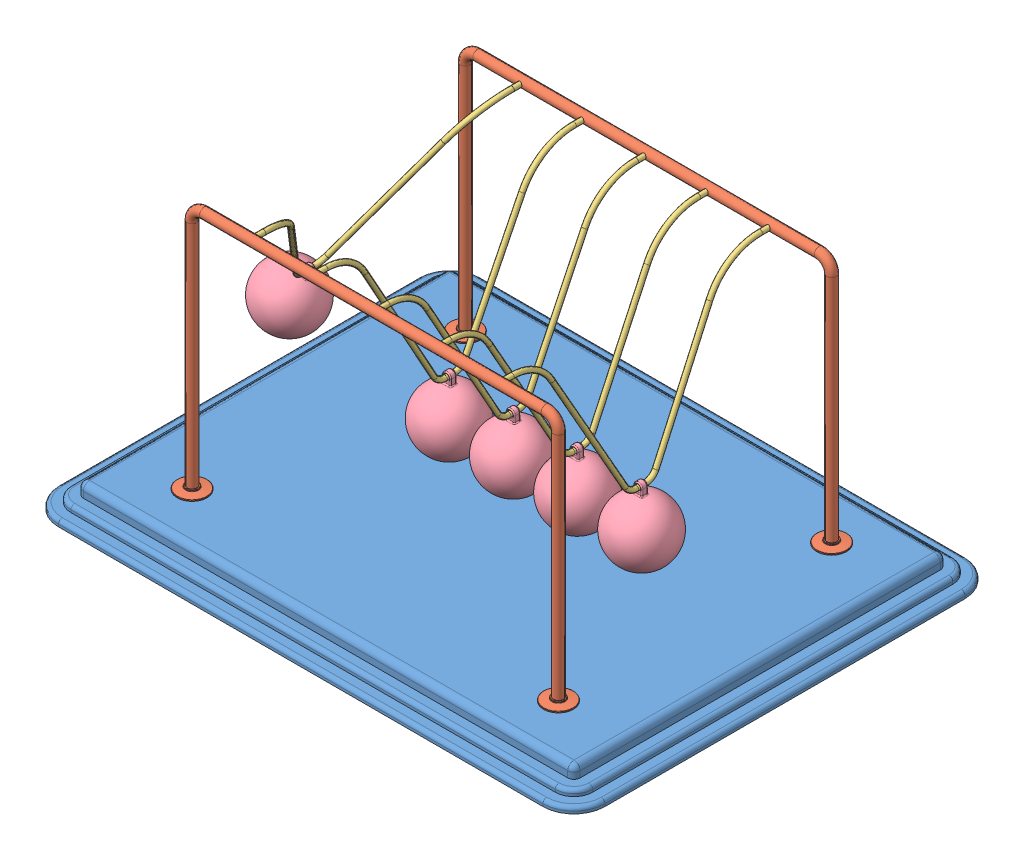
SolidWorks assembly Newtons Cradle NewtonsCradle 0252, configuration Default. Lengths in mm.
Overall size (440 222 340).
13 component instances, 4 part files, 34 mates.
Components (placement in the parent):
- Base 204.213938411669-1: Base 204.213938411669 [Default] at (-16.2968 -4.1587 11.425) size (440 20 340)
- frame NewtonsCradle 0252-1: frame NewtonsCradle 0252 [Default] at (-16.2968 144.4547 -98.575) size (319 202 24)
- frame NewtonsCradle 0252-2: frame NewtonsCradle 0252 [Default] at (-16.2968 144.4547 121.425) x (-1 0 0) z (0 0 -1) size (319 202 24)
- Hanging thing NewtonsCradle 0252-1: Hanging thing NewtonsCradle 0252 [Default] at (-157.6326 134.1825 11.425) x (0 0 1) z (-0.859985 0.510319 0) size (220 129 4)
- Hanging thing NewtonsCradle 0252-2: Hanging thing NewtonsCradle 0252 [Default] at (-66.576 122.8418 11.425) x (0 0 1) z (-0.999994 0.003446 0) size (220 129 4)
- Hanging thing NewtonsCradle 0252-3: Hanging thing NewtonsCradle 0252 [Default] at (-15.6923 122.8436 11.425) x (0 0 1) z (-0.999972 -0.007464 0) size (220 129 4)
- Hanging thing NewtonsCradle 0252-4: Hanging thing NewtonsCradle 0252 [Default] at (35.2213 122.8555 11.425) x (0 0 1) z (-0.999824 -0.018742 0) size (220 129 4)
- Hanging thing NewtonsCradle 0252-5: Hanging thing NewtonsCradle 0252 [Default] at (86.0287 122.8747 11.425) x (0 0 1) z (-0.999588 -0.028711 0) size (220 129 4)
- Sphere NewtonsCradle 0252-1: Sphere NewtonsCradle 0252 [Default] at (-195.3962 70.5436 11.425) x (0.859985 -0.510319 0) z (0 0 1) size (50 58.5 50)
- Sphere NewtonsCradle 0252-2: Sphere NewtonsCradle 0252 [Default] at (88.1533 48.9052 11.425) x (0.999588 0.028711 0) z (0 0 1) size (50 58.5 50)
- Sphere NewtonsCradle 0252-3: Sphere NewtonsCradle 0252 [Default] at (-15.14 48.8456 11.425) x (0.999972 0.007464 0) z (0 0 1) size (50 58.5 50)
- Sphere NewtonsCradle 0252-4: Sphere NewtonsCradle 0252 [Default] at (36.6081 48.8685 11.425) x (0.999824 0.018742 0) z (0 0 1) size (50 58.5 50)
- Sphere NewtonsCradle 0252-5: Sphere NewtonsCradle 0252 [Default] at (-66.831 48.8422 11.425) x (0.999994 -0.003446 0) z (0 0 1) size (50 58.5 50)
Mates (geometry in assembly coordinates):
- Coincident1: coincident anti-aligned: plane of Base-1 through (-211.2968 5.8413 156.425) normal (0 1 0); plane of frame-2 through (-175.7968 5.8413 121.425) normal (0 -1 0)
- Coincident2: coincident anti-aligned: plane of Base-1 through (-211.2968 5.8413 156.425) normal (0 1 0); plane of frame-1 through (143.2032 5.8413 -98.575) normal (0 -1 0)
- Concentric1: concentric anti-aligned: cylinder of frame-1 through (-116.2968 203.8413 -94.575) axis (0 0 -1) radius 2; cylinder of frame-2 through (-116.2968 203.8413 117.425) axis (0 0 1) radius 2
- Concentric2: concentric anti-aligned: cylinder of frame-1 through (83.7032 203.8413 -94.575) axis (0 0 -1) radius 2; cylinder of frame-2 through (83.7032 203.8413 117.425) axis (0 0 1) radius 2
- Distance1: distance = 60 mm: plane of frame-1 through (-16.2968 144.4547 -98.575) normal (0 0 1); line of Base-1 through (-211.2968 -12.1587 -158.575) axis (1 0 0)
- Distance2: distance = 60 mm: line of Base-1 through (178.7032 -12.1587 181.425) axis (-1 0 0); plane of frame-2 through (-16.2968 144.4547 121.425) normal (0 0 -1)
- Distance3: distance = 220 mm: plane of frame-2 through (-16.2968 144.4547 121.425) normal (-1 0 0); line of Base-1 through (-236.2968 -12.1587 156.425) axis (0 0 -1)
- Concentric3: concentric anti-aligned: cylinder of frame-1 through (-116.2968 203.8413 -94.575) axis (0 0 -1) radius 2; cylinder of Hanging thing-1 through (-116.2968 203.8413 111.425) axis (0 0 1) radius 2
- Concentric4: concentric anti-aligned: cylinder of frame-1 through (-116.2968 203.8413 -94.575) axis (0 0 -1) radius 2; cylinder of Hanging thing-1 through (-116.2968 203.8413 -98.575) axis (0 0 1) radius 2
- Concentric5: concentric aligned: cylinder of frame-2 through (-66.2968 203.8413 117.425) axis (0 0 1) radius 2; cylinder of Hanging thing-2 through (-66.2968 203.8413 111.425) axis (0 0 1) radius 2
- Concentric6: concentric aligned: cylinder of frame-2 through (-16.2968 203.8413 117.425) axis (0 0 1) radius 2; cylinder of Hanging thing-3 through (-16.2968 203.8413 111.425) axis (0 0 1) radius 2
- Concentric7: concentric aligned: cylinder of frame-2 through (33.7032 203.8413 117.425) axis (0 0 1) radius 2; cylinder of Hanging thing-4 through (33.7032 203.8413 111.425) axis (0 0 1) radius 2
- Concentric8: concentric aligned: cylinder of frame-2 through (83.7032 203.8413 117.425) axis (0 0 1) radius 2; cylinder of Hanging thing-5 through (83.7032 203.8413 111.425) axis (0 0 1) radius 2
- Coincident5: coincident anti-aligned: plane of frame-2 through (83.7032 203.8413 121.425) normal (0 0 -1); plane of Hanging thing-5 through (83.7032 203.8413 121.425) normal (0 0 1)
- Coincident6: coincident anti-aligned: plane of frame-2 through (33.7032 203.8413 121.425) normal (0 0 -1); plane of Hanging thing-4 through (33.7032 203.8413 121.425) normal (0 0 1)
- Coincident7: coincident anti-aligned: plane of frame-2 through (-16.2968 203.8413 121.425) normal (0 0 -1); plane of Hanging thing-3 through (-16.2968 203.8413 121.425) normal (0 0 1)
- Coincident8: coincident anti-aligned: plane of frame-2 through (-66.2968 203.8413 121.425) normal (0 0 -1); plane of Hanging thing-2 through (-66.2968 203.8413 121.425) normal (0 0 1)
- Coincident9: coincident anti-aligned: plane of frame-2 through (-116.2968 203.8413 121.425) normal (0 0 -1); plane of Hanging thing-1 through (-116.2968 203.8413 121.425) normal (0 0 1)
- Concentric9: concentric anti-aligned: cylinder of Hanging thing-1 through (-117.0163 78.8434 7.925) axis (0 0 1) radius 2; cylinder of Sphere-1 through (-117.0163 78.8434 13.925) axis (0 0 -1) radius 2
- Concentric13: concentric anti-aligned: cylinder of Hanging thing-2 through (-66.7276 78.842 7.925) axis (0 0 1) radius 2; cylinder of Sphere-5 through (-66.7276 78.842 13.925) axis (0 0 -1) radius 2
- Concentric15: concentric anti-aligned: cylinder of Hanging thing-3 through (-15.3639 78.8448 7.925) axis (0 0 1) radius 2; cylinder of Sphere-3 through (-15.3639 78.8448 13.925) axis (0 0 -1) radius 2
- Concentric16: concentric anti-aligned: cylinder of Hanging thing-5 through (87.292 78.8928 7.925) axis (0 0 1) radius 2; cylinder of Sphere-2 through (87.292 78.8928 13.925) axis (0 0 -1) radius 2
- Concentric17: concentric anti-aligned: cylinder of Hanging thing-4 through (36.0459 78.8632 7.925) axis (0 0 1) radius 2; cylinder of Sphere-4 through (36.0459 78.8632 13.925) axis (0 0 -1) radius 2
- Parallel1: parallel anti-aligned: plane of Hanging thing-1; plane of Sphere-1
- Coincident22: coincident anti-aligned: plane of Hanging thing-1; plane of Sphere-1
- Coincident12: coincident aligned: plane of Hanging thing-2 through (-66.576 122.8418 11.425) normal (0 0 1); plane of Sphere-5 through (-66.831 48.8422 11.425) normal (0 0 1)
- Coincident10: coincident aligned: plane of Hanging thing-1 through (-116.763 122.8426 11.425) normal (0 0 1); plane of Sphere-1 through (-118.5806 48.8842 11.425) normal (0 0 1)
- Coincident13: coincident anti-aligned: plane of Hanging thing-2 through (-66.576 122.8418 11.425) normal (-0.999994 0.003446 0); plane of Sphere-5 through (-66.831 48.8422 11.425) normal (0.999994 -0.003446 0)
- Coincident14: coincident anti-aligned: plane of Hanging thing-3 through (-15.6923 122.8436 11.425) normal (-0.999972 -0.007464 0); plane of Sphere-3 through (-15.14 48.8456 11.425) normal (0.999972 0.007464 0)
- Coincident15: coincident aligned: plane of Hanging thing-3 through (-15.6923 122.8436 11.425) normal (0 0 1); plane of Sphere-3 through (-15.14 48.8456 11.425) normal (0 0 1)
- Coincident18: coincident aligned: plane of Hanging thing-4 through (35.2213 122.8555 11.425) normal (0 0 1); plane of Sphere-4 through (36.6081 48.8685 11.425) normal (0 0 1)
- Coincident19: coincident anti-aligned: plane of Hanging thing-4 through (35.2213 122.8555 11.425) normal (-0.999824 -0.018742 0); plane of Sphere-4 through (36.6081 48.8685 11.425) normal (0.999824 0.018742 0)
- Coincident20: coincident anti-aligned: plane of Hanging thing-5 through (86.0287 122.8747 11.425) normal (-0.999588 -0.028711 0); plane of Sphere-2 through (88.1533 48.9052 11.425) normal (0.999588 0.028711 0)
- Coincident21: coincident aligned: plane of Hanging thing-5 through (86.0287 122.8747 11.425) normal (0 0 1); plane of Sphere-2 through (88.1533 48.9052 11.425) normal (0 0 1)
